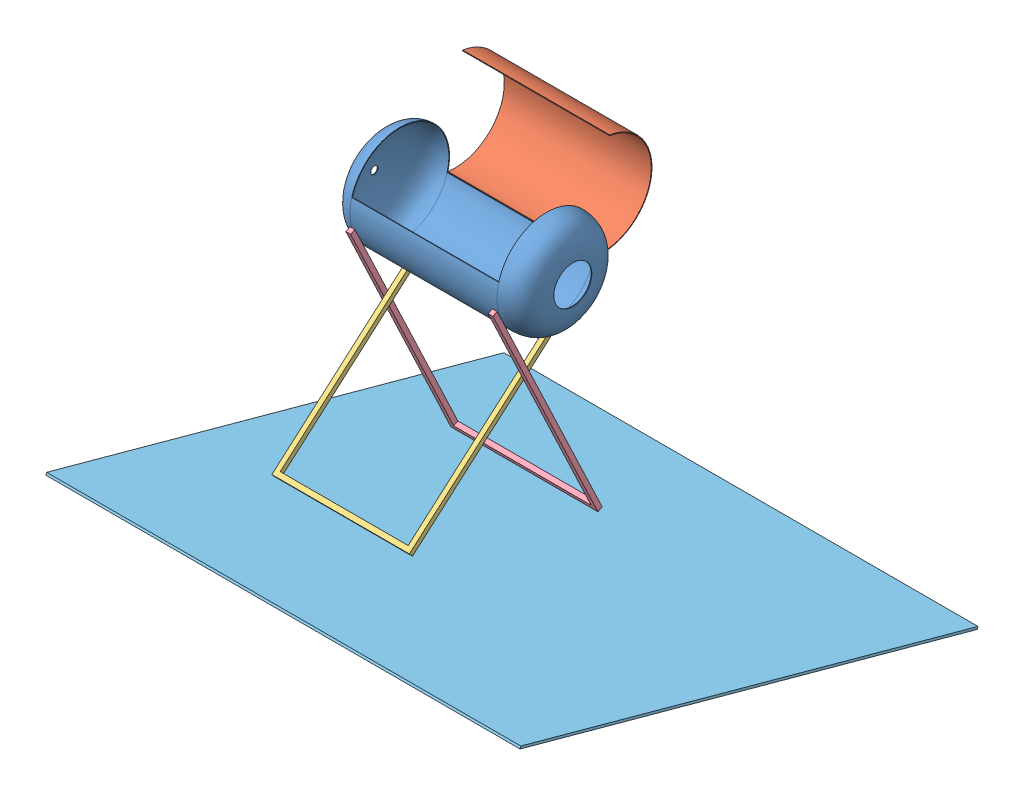
SolidWorks assembly Assem2, configuration Default. Lengths in mm.
Overall size (2054.95 1505.64 1931.78).
5 component instances, 5 part files, 9 mates.
Components (placement in the parent):
- ballon2-1: ballon2 [Default] at (365.4856 851.1865 1016.3885) x (1 0 0) z (0 0.263822 0.964571) size (1655.36 420 420)
- ballon3case-2: ballon3case [Default] at (365.4856 1394.7554 1036.9547) x (1 0 0) z (0 -0.988722 0.149761) size (620 210 420)
- keep 1-1: keep 1 [Default] at (428.2137 188.3548 1820.4315) x (1 0 0) z (0 -0.658375 0.75269) size (580 20 950)
- keep 2-1: keep 2 [Default] at (408.2137 2.7312 1108.9232) x (1 0 0) z (0 -0.903631 -0.428311) size (620 20 1035)
- bottom-1: bottom [Default] at (72.4493 327.7333 2551.8626) x (1 0 0) z (0 0.263822 0.964571) size (2000 10 2000)
Mates (geometry in assembly coordinates):
- Coincident3: coincident anti-aligned: line of ballon2-1 through (947.0695 878.2114 1115.1953) axis (-1 0 0); line of ballon3case-2 through (327.0695 878.2114 1115.1953) axis (1 0 0)
- Coincident4: coincident: point of ballon2-1; point of ballon3case-2
- Tangent1: tangent anti-aligned: cylinder of ballon2-1 through (-31.1065 933.614 1317.7553) axis (-1 0 0) radius 210; plane of keep 2-1 through (408.2137 2.7312 1108.9232) normal (0 0.428311 -0.903631)
- Tangent2: tangent anti-aligned: cylinder of ballon2-1 through (-31.1065 933.614 1317.7553) axis (-1 0 0) radius 210; plane of keep 1-1 through (428.2137 203.4086 1833.599) normal (0 0.75269 0.658375)
- Distance1: distance = 900 mm aligned: plane of ballon2-1 through (1970.3271 1045.7542 1727.7559) normal (0 0.964571 -0.263822); plane of bottom-1 through (72.4493 337.379 2549.2243) normal (0 0.964571 -0.263822)
- Coincident7: coincident: line of keep 1-1 through (347.0695 150.0293 1864.2472) axis (1 0 0); plane of bottom-1 through (72.4493 337.379 2549.2243) normal (0 0.964571 -0.263822)
- Coincident8: coincident: line of keep 2-1 through (327.0695 -58.4374 1102.063) axis (1 0 0); plane of bottom-1 through (72.4493 337.379 2549.2243) normal (0 0.964571 -0.263822)
- Coincident9: coincident anti-aligned: plane of ballon2-1 through (327.0695 851.1865 1016.3885) normal (1 0 0); plane of keep 2-1 through (327.0695 876.8212 1545.3646) normal (-1 0 0)
- Coincident10: coincident anti-aligned: plane of keep 1-1 through (927.0695 165.0832 1877.4147) normal (1 0 0); plane of keep 2-1 through (927.0695 876.8212 1545.3646) normal (-1 0 0)
